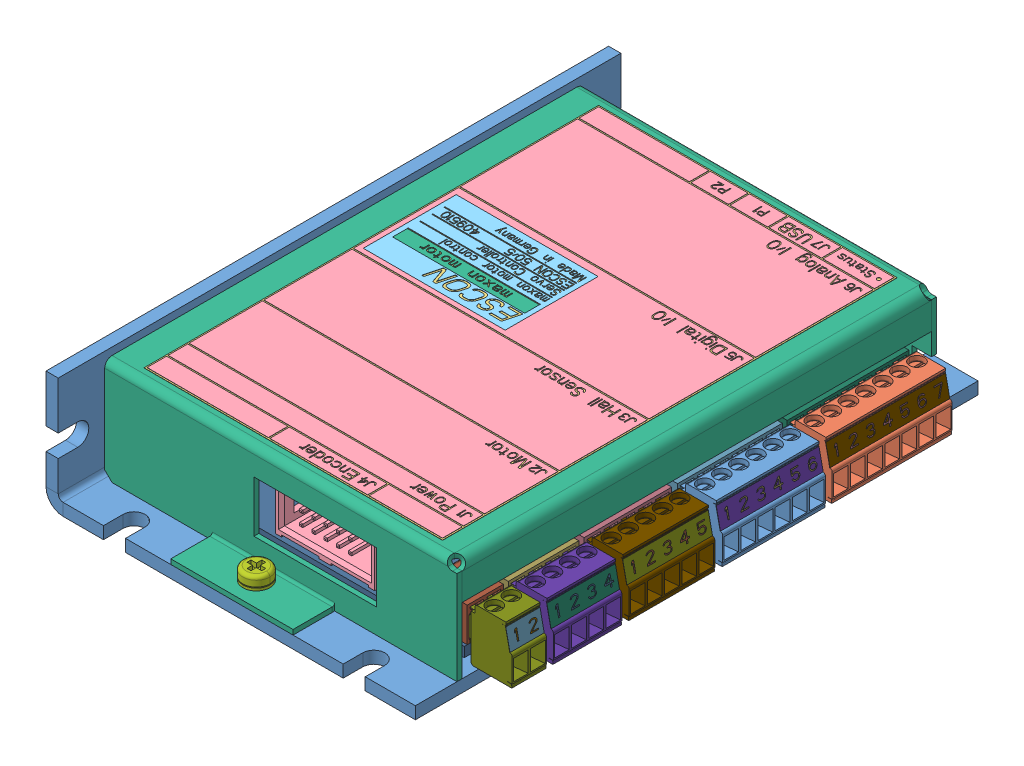
SolidWorks assembly 409510_escon_50_5, configuration Default. Lengths in mm.
Overall size (84.5 24.01 115).
49 component instances, 36 part files, 0 mates.
Components (placement in the parent):
- 409510_escon_50_5.stp-1: 409510_escon_50_5.stp [Default] at origin size (84.5 24.01 115)
  - HOUSING_BASEPLATE_CPL_50_5_ASM.stp-1: HOUSING_BASEPLATE_CPL_50_5_ASM.stp [Default] at (36 -8 0) x (0 0 -1) z (1 0 0) size (115 24.01 75.5)
    - HOUSING_BASEPLATE_50_5.stp-1: HOUSING_BASEPLATE_50_5.stp [Default] at origin size (115 24.01 75.5)
    - PEM-SO-3_5M3X6_A2A.stp-1: PEM-SO-3_5M3X6_A2A.stp [Default] at (-43.5 0 -14) x (0 -1 0) z (0 0 1) size (6.01 5.54 6.4)
    - PEM-SO-3_5M3X6_A2A.stp-2: PEM-SO-3_5M3X6_A2A.stp [Default] at (-43.5 0 -68) x (0 -1 0) z (0 0 1) size (6.01 5.54 6.4)
    - PEM-SO-3_5M3X6_A2A.stp-3: PEM-SO-3_5M3X6_A2A.stp [Default] at (43.5 0 -68) x (0 -1 0) z (0 0 1) size (6.01 5.54 6.4)
    - PEM-SO-3_5M3X6_A2A.stp-4: PEM-SO-3_5M3X6_A2A.stp [Default] at (43.5 0 -14) x (0 -1 0) z (0 0 1) size (6.01 5.54 6.4)
  - SILKSCREEN_50_5_ASM.stp-1: SILKSCREEN_50_5_ASM.stp [Default] at (0 15.5 0) x (-1 0 0) z (0 0 -1) size (61 0.1 92.9)
    - SILKSCREEN_BASE_61X93.stp-1: SILKSCREEN_BASE_61X93.stp [Default] at origin size (61 0.05 92.9)
    - SILKSCREEN_50_5_TEXT1.stp-1: SILKSCREEN_50_5_TEXT1.stp [Default] at (0 0.05 -3.95) size (60.4 0.05 92.3)
    - SILKSCREEN_LOGO_50_5.stp-1: SILKSCREEN_LOGO_50_5.stp [Default] at (14.7 0.05 6.55) size (29 0.05 19)
    - SILKSCREEN_MAXON_LOGO_27X3.stp-1: SILKSCREEN_MAXON_LOGO_27X3.stp [Default] at (14.7 0.05 3.55) size (27 0.05 3)
  - STATUS_INDICATOR_LED_ASM.stp-1: STATUS_INDICATOR_LED_ASM.stp [Default] at (33.375 0 -45.175) x (0 0 1) z (0 -1 0) size (1.65 2.25 0.62)
    - LED_BASE.stp-1: LED_BASE.stp [Default] at (0 0.7625 0) x (1 0 0) z (0 0 -1) size (1.65 0.73 0.35)
    - LED_BASE.stp-2: LED_BASE.stp [Default] at (0 -0.7625 0) x (-1 0 0) z (0 0 -1) size (1.65 0.73 0.35)
    - LED_GREEN.stp-1: LED_GREEN.stp [Default] at (0 0.7625 -0.325) x (1 0 0) z (0 1 0) size (1 0.3 0.65)
    - LED_RED.stp-1: LED_RED.stp [Default] at (0 -0.7625 -0.325) x (1 0 0) z (0 1 0) size (1 0.3 0.65)
  - PRINTED_BOARD_50_5.stp-1: PRINTED_BOARD_50_5.stp [Default] x (0 0 -1) z (-1 0 0) size (95 2 72)
  - J1_POWER_PIN.stp-1: J1_POWER_PIN.stp [Default] at (36 0 44.95) size (9.2 10.4 7.4)
  - J2_MOTOR_PIN.stp-1: J2_MOTOR_PIN.stp [Default] at (36 0 36.55) size (9.2 10.4 14.4)
  - J3_HALL_SENSOR_PIN.stp-1: J3_HALL_SENSOR_PIN.stp [Default] at (36 0 21.05) size (9.2 10.4 17.9)
  - J5_DIGITAL_IOS_PIN.stp-1: J5_DIGITAL_IOS_PIN.stp [Default] at (36 0 1.95) size (9.2 10.4 21.4)
  - J6_ANALOG_IOS_PIN.stp-1: J6_ANALOG_IOS_PIN.stp [Default] at (36 0 -20.45) size (9.2 10.4 24.9)
  - J1_POWER_PLUG.stp-1: J1_POWER_PLUG.stp [Default] at (45 -3.35 41.45) x (-1 0 0) z (0 0 -1) size (15.6 11.1 7)
  - J2_MOTOR_PLUG.stp-1: J2_MOTOR_PLUG.stp [Default] at (45 -3.35 26.05) x (-1 0 0) z (0 0 -1) size (15.6 11.1 14)
  - J3_HALL_SENSOR_PLUG.stp-1: J3_HALL_SENSOR_PLUG.stp [Default] at (45 -3.35 7.05) x (-1 0 0) z (0 0 -1) size (15.6 11.1 17.5)
  - J5_DIGITAL_IOS_PLUG.stp-1: J5_DIGITAL_IOS_PLUG.stp [Default] at (45 -3.35 -15.55) x (-1 0 0) z (0 0 -1) size (15.6 11.1 21)
  - J6_ANALOG_IOS_PLUG.stp-1: J6_ANALOG_IOS_PLUG.stp [Default] at (45 -3.35 -41.45) x (-1 0 0) z (0 0 -1) size (15.6 11.1 24.5)
  - P_POTENTIOMETER_2.stp-1: P_POTENTIOMETER_2.stp [Default] at (6.03 0.3 -47.46) x (0 0 -1) z (0 -1 0) size (5.21 6.7 8.53)
  - P_POTENTIOMETER_2.stp-2: P_POTENTIOMETER_2.stp [Default] at (-0.97 0.3 -47.46) x (0 0 -1) z (0 -1 0) size (5.21 6.7 8.53)
  - J4_ENCODER_SOCKET_2.stp-1: J4_ENCODER_SOCKET_2.stp [Default] at (7.01 9.444 38.1) x (-1 0 0) z (0 1 0) size (20.3 12.62 12.18)
  - M3X8.stp-1: M3X8.stp [Default] at (-32 2.6 43.5) x (0 1 0) z (0 0 1) size (10 5.5 5.5)
  - M3X8.stp-2: M3X8.stp [Default] at (22 2.6 43.5) x (0 1 0) z (0 0 1) size (10 5.5 5.5)
  - M3X8.stp-3: M3X8.stp [Default] at (-32 2.6 -43.5) x (0 1 0) z (0 0 1) size (10 5.5 5.5)
  - M3X8.stp-4: M3X8.stp [Default] at (22 2.6 -43.5) x (0 1 0) z (0 0 1) size (10 5.5 5.5)
  - HOUSING_COVER_50_5.stp-1: HOUSING_COVER_50_5.stp [Default] at (-1.5 15.5 0) x (0 0 -1) z (1 0 0) size (115 21.01 72)
  - M3X4.stp-1: M3X4.stp [Default] at (-1.5 -1.9 52.5) x (0 1 0) z (0 0 1) size (6 5.5 5.5)
  - M3X4.stp-2: M3X4.stp [Default] at (-1.5 -1.9 -52.5) x (0 1 0) z (0 0 1) size (6 5.5 5.5)
  - J7_USB.stp-1: J7_USB.stp [Default] at (13.99 0 -48.18) x (-1 0 0) z (0 0 -1) size (8.12 3.11 5.6)
  - SILKSCREEN_12_BASE.stp-1: SILKSCREEN_12_BASE.stp [Default] at (44.0657 4.8155 41.45) x (0 0 1) z (-0.20578 0.978598 0) size (7 0.02 4.2)
  - SILKSCREEN_1234_BASE.stp-1: SILKSCREEN_1234_BASE.stp [Default] at (44.0657 4.8155 36.55) x (0 0 -1) z (0.20578 -0.978598 0) size (14 0.02 4.2)
  - SILKSCREEN_12345_BASE.stp-1: SILKSCREEN_12345_BASE.stp [Default] at (44.0657 4.8155 7.05) x (0 0 1) z (-0.20578 0.978598 0) size (17.5 0.02 4.2)
  - SILKSCREEN_123456_BASE.stp-1: SILKSCREEN_123456_BASE.stp [Default] at (44.0852 4.8196 -15.55) x (0 0 1) z (0.20578 -0.978598 0) size (21 0.02 4.2)
  - SILKSCREEN_1234567_BASE.stp-1: SILKSCREEN_1234567_BASE.stp [Default] at (44.0657 4.8155 -41.45) x (0 0 1) z (-0.20578 0.978598 0) size (24.5 0.02 4.2)
  - SILKSCREEN_12.stp-1: SILKSCREEN_12.stp [Default] at (44.0852 4.8196 44.95) x (0 0 -1) z (0.20578 -0.978598 0) size (7 0.02 4.2)
  - SILKSCREEN_1234.stp-1: SILKSCREEN_1234.stp [Default] at (44.0852 4.8196 36.55) x (0 0 -1) z (0.20578 -0.978598 0) size (14 0.02 4.2)
  - SILKSCREEN_12345.stp-1: SILKSCREEN_12345.stp [Default] at (44.0852 4.8196 21.05) x (0 0 -1) z (0.20578 -0.978598 0) size (17.5 0.02 4.2)
  - SILKSCREEN_123456.stp-1: SILKSCREEN_123456.stp [Default] at (44.1048 4.8238 1.95) x (0 0 -1) z (0.20578 -0.978598 0) size (21 0.02 4.2)
  - SILKSCREEN_1234567.stp-1: SILKSCREEN_1234567.stp [Default] at (44.0852 4.8196 -20.45) x (0 0 -1) z (0.20578 -0.978598 0) size (24.5 0.02 4.2)
